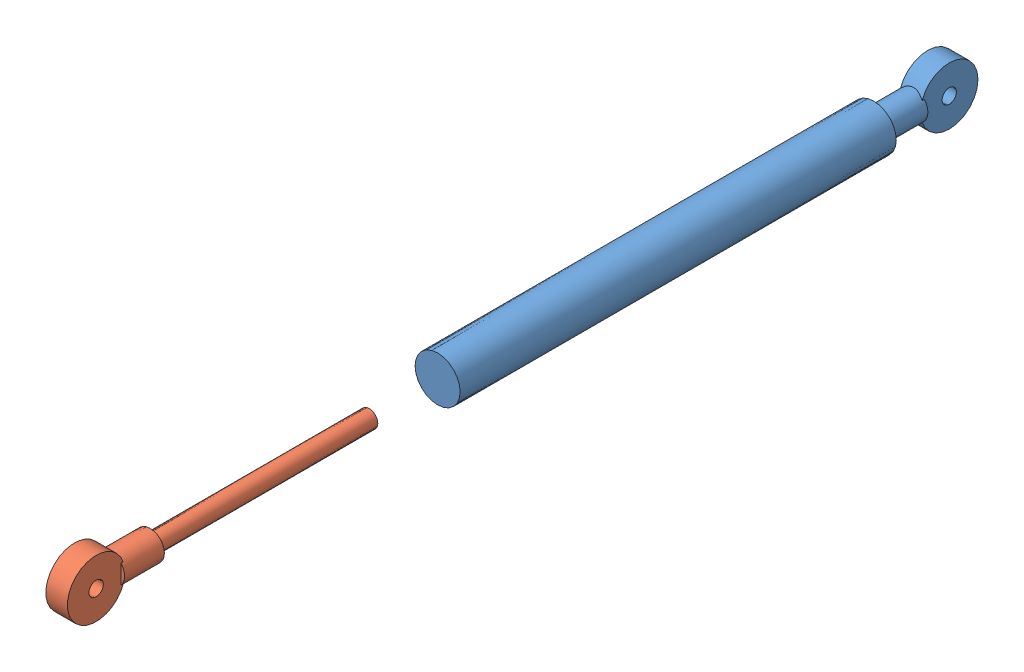
SolidWorks assembly KA94B Mated Assembly, configuration Default. Lengths in mm.
Overall size (9.4 12 190).
2 component instances, 2 part files, 2 mates.
Components (placement in the parent):
- KA94B sensor body (body)-1: KA94B sensor body (body) [Default] at (-48.2637 -35.9474 0.6402) size (9.4 12 110.5)
- KA94B Sensor Stantion-1: KA94B Sensor Stantion [Default] at (-48.2637 -35.9474 14.9193) size (6 12 65.22)
Mates (geometry in assembly coordinates):
- Concentric2: concentric anti-aligned: cylinder of KA94B sensor body (body)-1 through (-48.2637 -35.9474 14.1402) axis (0 0 -1) radius 4.7; cylinder of KA94B Sensor Stantion-1 through (-48.2637 -35.9474 165.1402) axis (0 0 1) radius 1.8
- LimitDistance2: limit distance = 175 mm: cylinder of KA94B Sensor Stantion-1 through (-46.0137 -35.9474 178.6402) axis (-1 0 0) radius 1.5; cylinder of KA94B sensor body (body)-1 through (-46.0137 -35.9474 0.6402) axis (-1 0 0) radius 1.5
